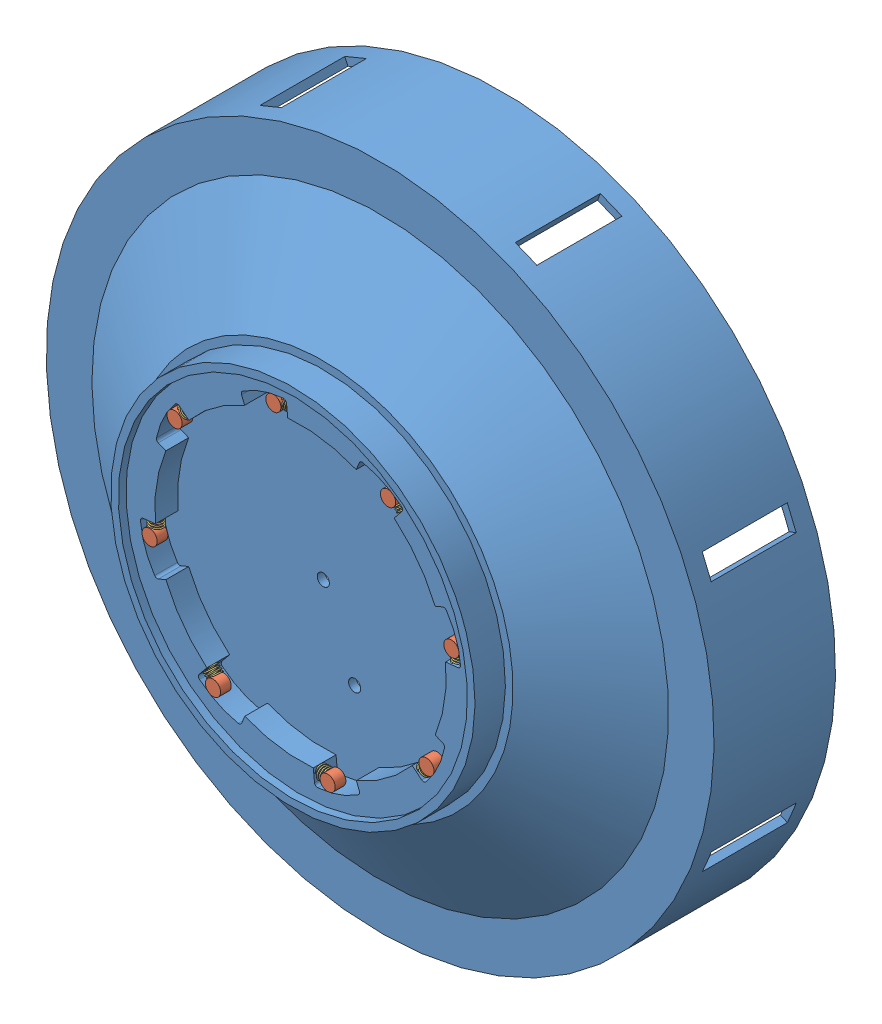
SolidWorks assembly trappedRollerBearing, configuration Default. Lengths in mm.
Overall size (287.49 287.49 68.75).
17 component instances, 3 part files, 4 mates.
Components (placement in the parent):
- casing-1: casing [Default] at (98.9757 122.8158 -11.25) x (-0.923728 -0.383049 0) z (0 0 -1) size (220 220 68.75)
- trappedRollers-1: trappedRollers [Default] at (90.0277 172.518 -6) x (-0.875937 -0.482425 0) z (0 0 1) size (5 5 3.5)
- trappedRollers-2: trappedRollers [Default] at (127.7932 164.2878 -6) x (-0.960507 0.278255 0) z (0 0 1) size (5 5 3.5)
- trappedRollers-3: trappedRollers [Default] at (148.6778 131.7639 -6) x (-0.482425 0.875937 0) z (0 0 1) size (5 5 3.5)
- trappedRollers-4: trappedRollers [Default] at (140.4476 93.9983 -6) x (0.278255 0.960507 0) z (0 0 1) size (5 5 3.5)
- trappedRollers-5: trappedRollers [Default] at (107.9237 73.1137 -6) x (0.875937 0.482425 0) z (0 0 1) size (5 5 3.5)
- trappedRollers-6: trappedRollers [Default] at (70.1582 81.3439 -6) x (0.960507 -0.278255 0) z (0 0 1) size (5 5 3.5)
- trappedRollers-7: trappedRollers [Default] at (49.2736 113.8678 -6) x (0.482425 -0.875937 0) z (0 0 1) size (5 5 3.5)
- trappedRollers-8: trappedRollers [Default] at (57.5038 151.6333 -6) x (-0.278255 -0.960507 0) z (0 0 1) size (5 5 3.5)
- spring-1: spring [Default] at (95.1457 172.8042 -5) x (0 1 0) z (-1 0 0) size (4.35 4.35 3.91)
- spring-2: spring [Default] at (131.6146 160.8712 -5) x (0.707107 0.707107 0) z (-0.707107 0.707107 0) size (4.35 4.35 3.91)
- spring-3: spring [Default] at (148.964 126.6459 -5) x (1 0 0) z (0 1 0) size (4.35 4.35 3.91)
- spring-4: spring [Default] at (137.031 90.177 -5) x (0.707107 -0.707107 0) z (0.707107 0.707107 0) size (4.35 4.35 3.91)
- spring-5: spring [Default] at (102.8057 72.8275 -5) x (0 -1 0) z (1 0 0) size (4.35 4.35 3.91)
- spring-6: spring [Default] at (66.3369 84.7605 -5) x (-0.707107 -0.707107 0) z (0.707107 -0.707107 0) size (4.35 4.35 3.91)
- spring-7: spring [Default] at (48.9874 118.9858 -5) x (-1 0 0) z (0 -1 0) size (4.35 4.35 3.91)
- spring-8: spring [Default] at (60.9204 155.4547 -5) x (-0.707107 0.707107 0) z (-0.707107 -0.707107 0) size (4.35 4.35 3.91)
Mates (geometry in assembly coordinates):
- Coincident1: coincident: plane of assembly through (0 0 0) normal (0 0 1); plane of casing-1 through (98.9757 122.8158 0) normal (0 0 1); plane of assembly
- Coincident2: coincident: plane of assembly; plane of assembly; plane of casing-1 through (98.9757 122.8158 -2.5) normal (0 0 1); plane of trappedRollers-1 through (90.0277 172.518 -2.5) normal (0 0 1)
- Tangent2: tangent: cylinder of assembly; cylinder of assembly; cylinder of casing-1 through (95.6498 147.4035 0) axis (0 0 -1) radius 28.236; cylinder of trappedRollers-1 through (90.0277 172.518 -2.5) axis (0 0 -1) radius 2.5
- Distance1: distance = 2.5 mm: plane of assembly; plane of assembly; plane of spring-1 through (95.1457 172.8042 -5) normal (0 0 -1); plane of casing-1 through (98.9757 122.8158 -2.5) normal (0 0 1)
